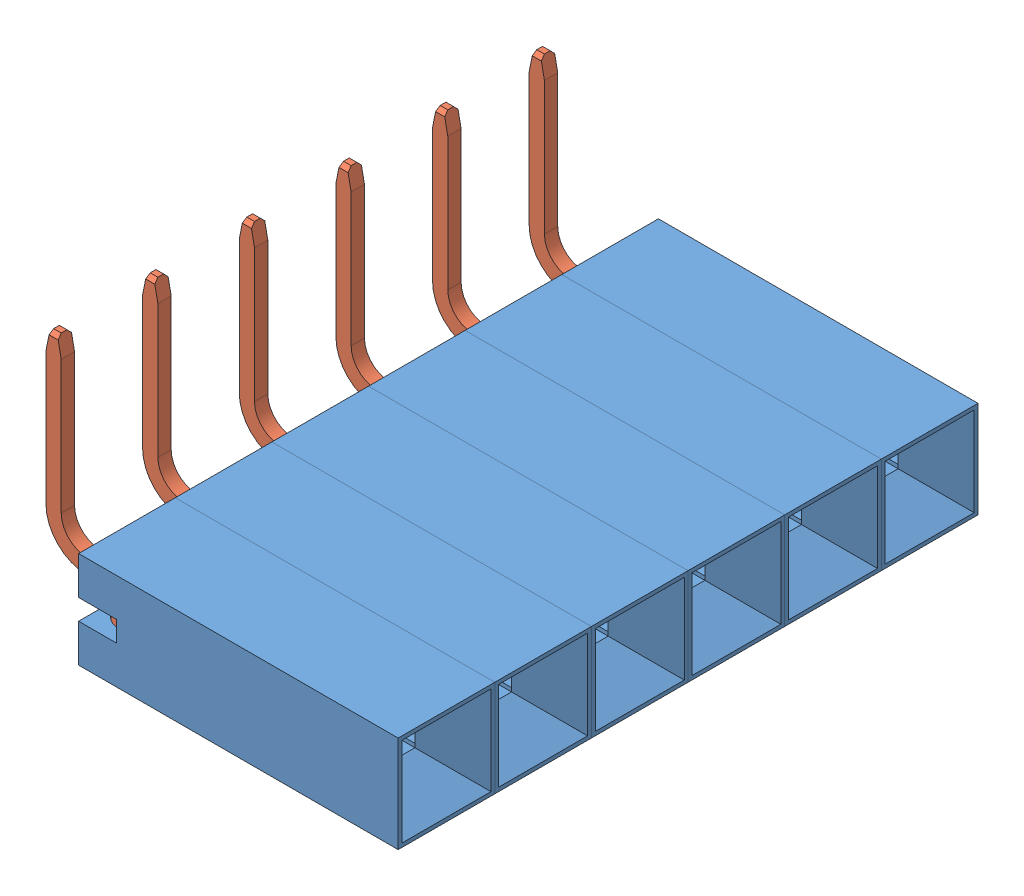
SolidWorks assembly H254_90deg_6pin, configuration Default. Lengths in mm.
Overall size (10.36 6.14 15.24).
20 component instances, 2 part files, 2 mates.
Components (placement in the parent):
- H254_90deg_3pin-1: H254_90deg_3pin [Default] at origin size (10.36 6.14 7.62)
  - FrameAndPin_H254_90deg-1: FrameAndPin_H254_90deg [Default] at origin size (10.36 6.14 2.54)
    - frame_H254-1: frame_H254 [Default] at origin size (8.4 2.54 2.54)
    - pin-90deg-1: pin-90deg [Default] at (-0.0461 1.2682 1.27) x (0 0 -1) z (0.999998 -0.002105 0) size (1.95 5.07 7.58)
  - FrameAndPin_H254_90deg-2: FrameAndPin_H254_90deg [Default] at (0 0 -2.54) size (10.36 6.14 2.54)
    - frame_H254-1: frame_H254 [Default] at origin size (8.4 2.54 2.54)
    - pin-90deg-1: pin-90deg [Default] at (-0.0461 1.2682 1.27) x (0 0 -1) z (0.999998 -0.002105 0) size (1.95 5.07 7.58)
  - FrameAndPin_H254_90deg-4: FrameAndPin_H254_90deg [Default] at (0 0 -5.08) size (10.36 6.14 2.54)
    - frame_H254-1: frame_H254 [Default] at origin size (8.4 2.54 2.54)
    - pin-90deg-1: pin-90deg [Default] at (-0.0461 1.2682 1.27) x (0 0 -1) z (0.999998 -0.002105 0) size (1.95 5.07 7.58)
- H254_90deg_3pin-2: H254_90deg_3pin [Default] at (0 0 -7.62) size (10.36 6.14 7.62)
  - FrameAndPin_H254_90deg-1: FrameAndPin_H254_90deg [Default] at origin size (10.36 6.14 2.54)
    - frame_H254-1: frame_H254 [Default] at origin size (8.4 2.54 2.54)
    - pin-90deg-1: pin-90deg [Default] at (-0.0461 1.2682 1.27) x (0 0 -1) z (0.999998 -0.002105 0) size (1.95 5.07 7.58)
  - FrameAndPin_H254_90deg-2: FrameAndPin_H254_90deg [Default] at (0 0 -2.54) size (10.36 6.14 2.54)
    - frame_H254-1: frame_H254 [Default] at origin size (8.4 2.54 2.54)
    - pin-90deg-1: pin-90deg [Default] at (-0.0461 1.2682 1.27) x (0 0 -1) z (0.999998 -0.002105 0) size (1.95 5.07 7.58)
  - FrameAndPin_H254_90deg-4: FrameAndPin_H254_90deg [Default] at (0 0 -5.08) size (10.36 6.14 2.54)
    - frame_H254-1: frame_H254 [Default] at origin size (8.4 2.54 2.54)
    - pin-90deg-1: pin-90deg [Default] at (-0.0461 1.2682 1.27) x (0 0 -1) z (0.999998 -0.002105 0) size (1.95 5.07 7.58)
Mates (geometry in assembly coordinates):
- Coincident1: coincident: line of H254_90deg_3pin-1/FrameAndPin_H254_90deg-4/frame_H254-1 through (8.4 2.54 -5.08) axis (-1 0 0); line of ? through (12.4497 2.54 -5.08) axis (-1 0 0)
- Coincident2: coincident: line of assembly; line of assembly; line of H254_90deg_3pin-1/FrameAndPin_H254_90deg-4/frame_H254-1 through (8.4 0 -5.08) axis (0 1 0); line of H254_90deg_3pin-2/FrameAndPin_H254_90deg-1/frame_H254-1 through (8.4 0 -5.08) axis (0 1 0)
